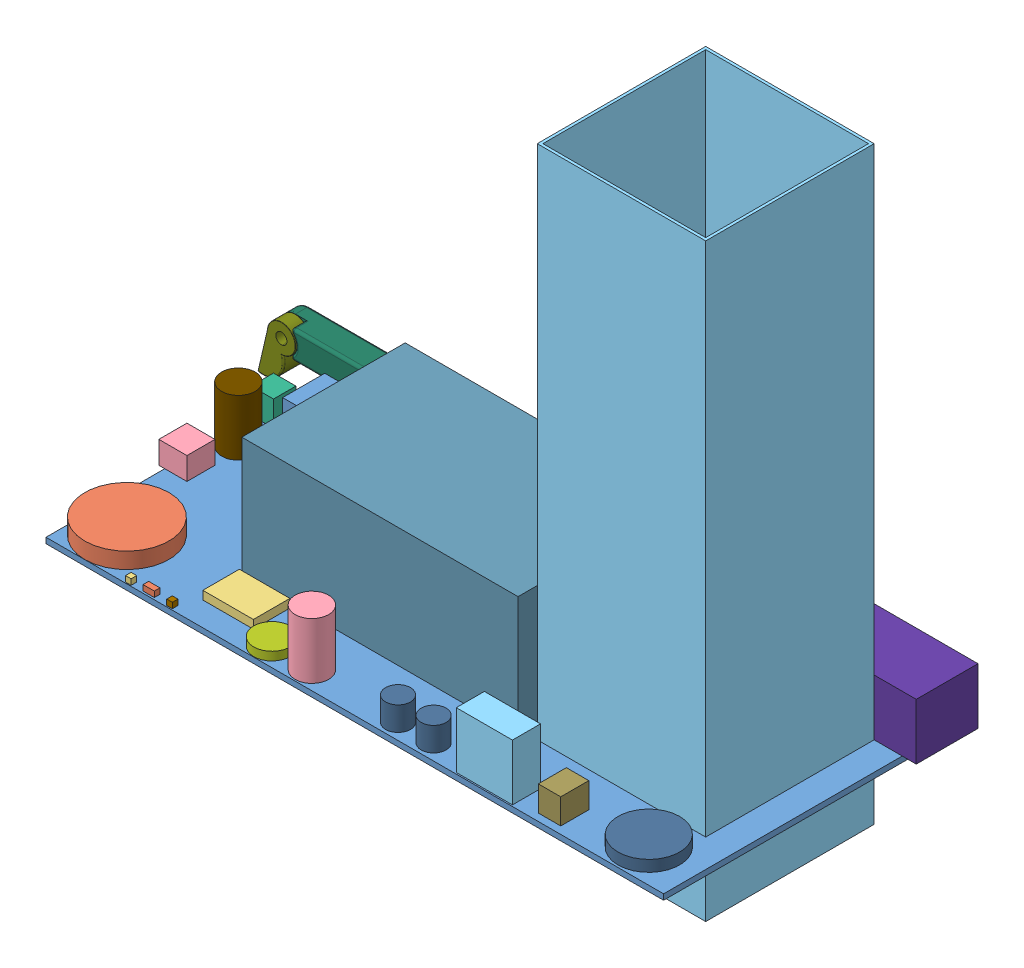
SolidWorks assembly layout_Assem1_rev2, configuration Default. Lengths in mm.
Overall size (2479.25 2100 1119.03).
31 component instances, 28 part files, 39 mates.
Components (placement in the parent):
- Rover_base-1: Rover_base [Default] at (-1064.6676 -0.8898 562.4151) size (2200 20 1100)
- Neutron_spectrometer-1: Neutron_spectrometer [Default] at (-926.7762 19.1102 412.2415) size (300 57 300)
- Neutron_spectrometer_electronics-1: Neutron_spectrometer_electronics [Default] at (-591.6675 19.1102 476.7062) size (180 30 130)
- gc-1: gc [Default] at (-1085.6976 19.1102 139.436) size (100 80 100)
- svr_box-1: svr_box [Default] at (435.3324 -241.6306 312.4151) size (600 2100 600)
- xrf-1: xrf [Default] at (-995.9409 19.1102 -179.1913) size (80 90 80)
- geotechnical_exp-1: geotechnical_exp [Default] at (-326.3032 19.1102 495.7882) x (0.972542 0 0.232729) z (-0.232729 0 0.972542) size (130 30 130)
- penetrometer_3-1: penetrometer_3 [Default] at (226.7911 19.1102 -521.6787) x (-0.361814 0 0.93225) z (-0.93225 0 -0.361814) size (20 40 20)
- penetrometer_3-2: penetrometer_3 [Default] at (171.3766 19.1102 -523.8951) size (20 40 20)
- penetrometer_3-3: penetrometer_3 [Default] at (128.071 19.1102 -518.5402) x (0.588244 0 -0.808683) z (0.808683 0 0.588244) size (20 40 20)
- power-1: power [Default] at (-481.4265 19.1102 -288.1678) size (180 90 96)
- geotechnical_exp_vane-1: geotechnical_exp_vane [Default] at (965.2252 19.1102 444.9326) size (220 40 220)
- Magnents-1: Magnents [Default] at (-1020.4169 -10.8898 98.2252) size (45 10 45)
- Becon-1: Becon [Default] at (742.9179 19.1102 536.3746) size (80 90 100)
- Belly Cam-1: Belly Cam [Default] at (-624.94 -100.8898 134.6139) size (150 100 150)
- lithium_battery_pack-1: lithium_battery_pack [Default] at (-598.6676 19.1102 330.9157) size (984 426 582)
- arm-1: arm [Default] at (-1208.8877 19.1102 -520.2644) x (-1 0 0) z (0 0 -1) size (1100 100 100)
- scoop-1: scoop [Default] at (-1258.8868 69.4182 -520.2644) x (0.225074 0.974342 0) z (0.974342 -0.225074 0) size (211.36 101.82 100)
- drill-1: drill [Default] at (1185.3324 19.1102 -287.5849) size (500 200 220)
- ap spectrometer-1: ap spectrometer [Default] at (-1001.9092 219.1102 -60.2814) x (0.2867 0 0.958021) z (0 -1 0) size (120 120 200)
- eprs-1: eprs [Default] at (-873.9785 19.1102 -239.8403) size (200 200 150)
- helium 3 sensor-1: helium 3 sensor [Default] at (-685.7595 19.1102 535.5303) size (40 20 20)
- ir bolometer-1: ir bolometer [Default] at (-784.8936 19.1102 538.9968) size (20 20 20)
- gamma ray spectrometer-1: gamma ray spectrometer [Default] at (-182.4638 19.1102 497.4632) x (0.580646 0 0.814156) z (0 1 0) size (120 120 200)
- langmuir probe-1: langmuir probe [Default] at (391.7791 19.1102 457.3324) size (200 200 100)
- particle counter-1: particle counter [Default] at (636.3286 19.1102 -531.248) x (0 0 1) z (-1 0 0) size (200 300 300)
- pes-1: pes [Default] at (-49.2556 19.1102 -529.0851) size (100 200 100)
- tuneable diode laser-1: tuneable diode laser [Default] at (299.0429 19.1102 -537.8756) size (10 10 10)
- uv imaging-1: uv imaging [Default] at (-638.9228 19.1102 538.0436) size (20 20 20)
- IMU_2-1: IMU_2 [Default] at (260.0364 19.1102 506.2504) size (88.9 85.09 88.9)
- IMU_2-2: IMU_2 [Default] at (133.304 19.1102 506.3815) size (88.9 85.09 88.9)
Mates (geometry in assembly coordinates):
- Coincident2: coincident anti-aligned: plane of Rover_base-1 through (-1064.6676 19.1102 -537.5849) normal (0 1 0); plane of Neutron_spectrometer-1 through (-926.7762 19.1102 412.2415) normal (0 -1 0)
- Coincident6: coincident anti-aligned: plane of Rover_base-1 through (-1064.6676 19.1102 -537.5849) normal (0 1 0); plane of Neutron_spectrometer_electronics-1 through (-591.6675 19.1102 346.7062) normal (0 -1 0)
- Coincident7: coincident anti-aligned: plane of Rover_base-1 through (-1064.6676 19.1102 -537.5849) normal (0 1 0); plane of power-1 through (-481.4265 19.1102 -384.1678) normal (0 -1 0)
- Coincident8: coincident anti-aligned: plane of Rover_base-1 through (-1064.6676 19.1102 -537.5849) normal (0 1 0); plane of gc-1 through (-1085.6976 19.1102 39.436) normal (0 -1 0)
- Coincident9: coincident aligned: plane of Rover_base-1 through (-1064.6676 19.1102 -537.5849) normal (0 1 0); circle of geotechnical_exp-1 centre (-326.3032 19.1102 495.7882) axis (0 1 0)
- Coincident10: coincident anti-aligned: plane of Rover_base-1 through (-1064.6676 19.1102 -537.5849) normal (0 1 0); plane of xrf-1 through (-995.9409 19.1102 -179.1913) normal (0 -1 0)
- Coincident11: coincident aligned: plane of Rover_base-1 through (-1064.6676 19.1102 -537.5849) normal (0 1 0); circle of penetrometer_3-3 centre (128.071 19.1102 -518.5402) axis (0 1 0)
- Coincident12: coincident anti-aligned: plane of Rover_base-1 through (-1064.6676 19.1102 -537.5849) normal (0 1 0); plane of penetrometer_3-2 through (171.3766 19.1102 -523.8951) normal (0 -1 0)
- Coincident13: coincident aligned: plane of Rover_base-1 through (-1064.6676 19.1102 -537.5849) normal (0 1 0); circle of penetrometer_3-1 centre (226.7911 19.1102 -521.6787) axis (0 1 0)
- Coincident14: coincident anti-aligned: plane of Rover_base-1 through (-1064.6676 19.1102 -537.5849) normal (0 1 0); plane of geotechnical_exp_vane-1 through (965.2252 19.1102 444.9326) normal (0 -1 0)
- Coincident15: coincident anti-aligned: plane of Rover_base-1 through (-1064.6676 -0.8898 -537.5849) normal (0 -1 0); plane of Magnents-1 through (-1020.4169 -0.8898 98.2252) normal (0 1 0)
- Coincident16: coincident anti-aligned: plane of Rover_base-1 through (-1064.6676 19.1102 -537.5849) normal (0 1 0); plane of Becon-1 through (742.9179 19.1102 536.3746) normal (0 -1 0)
- Coincident18: coincident: line of Rover_base-1; plane of svr_box-1 through (435.3324 1858.3694 312.4151) normal (-1 0 0)
- Coincident20: coincident: line of Rover_base-1; plane of svr_box-1 through (435.3324 1858.3694 -287.5849) normal (0 0 -1)
- Perpendicular2: perpendicular: line of Rover_base-1; line of svr_box-1
- Perpendicular3: perpendicular: line of Rover_base-1; line of svr_box-1
- Perpendicular4: perpendicular: line of Rover_base-1; line of svr_box-1
- Coincident21: coincident anti-aligned: plane of Rover_base-1 through (-1064.6676 19.1102 -537.5849) normal (0 1 0); plane of lithium_battery_pack-1 through (-598.6676 19.1102 -251.0843) normal (0 -1 0)
- Distance1: distance = 50 mm anti-aligned: plane of svr_box-1 through (435.3324 1858.3694 312.4151) normal (-1 0 0); plane of lithium_battery_pack-1 through (385.3324 445.1102 330.9157) normal (1 0 0)
- Coincident23: coincident anti-aligned: plane of Rover_base-1 through (-1064.6676 19.1102 -537.5849) normal (0 1 0); plane of arm-1 through (-1208.8877 19.1102 -420.2644) normal (0 -1 0)
- Distance2: distance = 100 mm: line of Rover_base-1; point of arm-1
- Distance3: distance = 20 mm: line of Rover_base-1; line of arm-1
- Coincident27: coincident aligned: circle of arm-1 centre (-1208.8877 69.1102 -470.2644) axis (0 0 1); circle of scoop-1 centre (-1208.8877 69.1102 -470.2644) axis (0 0 1)
- Coincident28: coincident anti-aligned: plane of Rover_base-1 through (-1064.6676 19.1102 -537.5849) normal (0 1 0); plane of drill-1 through (1185.3324 19.1102 -507.5849) normal (0 -1 0)
- Coincident29: coincident anti-aligned: plane of svr_box-1 through (435.3324 1858.3694 -287.5849) normal (0 0 -1); plane of drill-1 through (1185.3324 219.1102 -287.5849) normal (0 0 1)
- Distance4: distance = 50 mm: line of Rover_base-1; plane of drill-1 through (1185.3324 219.1102 -287.5849) normal (1 0 0)
- Coincident31: coincident anti-aligned: plane of Rover_base-1 through (-1064.6676 19.1102 -537.5849) normal (0 1 0); plane of ap spectrometer-1 through (-1001.9092 19.1102 -60.2814) normal (0 -1 0)
- Coincident32: coincident anti-aligned: plane of Rover_base-1 through (-1064.6676 19.1102 -537.5849) normal (0 1 0); plane of eprs-1 through (-873.9785 19.1102 -89.8403) normal (0 -1 0)
- Coincident33: coincident anti-aligned: plane of Rover_base-1 through (-1064.6676 19.1102 -537.5849) normal (0 1 0); plane of helium 3 sensor-1 through (-725.7595 19.1102 555.5303) normal (0 -1 0)
- Coincident34: coincident anti-aligned: plane of Rover_base-1 through (-1064.6676 19.1102 -537.5849) normal (0 1 0); plane of ir bolometer-1 through (-784.8936 19.1102 558.9968) normal (0 -1 0)
- Coincident36: coincident anti-aligned: plane of Rover_base-1 through (-1064.6676 19.1102 -537.5849) normal (0 1 0); plane of gamma ray spectrometer-1 through (-182.4638 19.1102 497.4632) normal (0 -1 0)
- Coincident37: coincident anti-aligned: plane of Rover_base-1 through (-1064.6676 19.1102 -537.5849) normal (0 1 0); plane of langmuir probe-1 through (391.7791 19.1102 557.3324) normal (0 -1 0)
- Coincident38: coincident: plane of Rover_base-1 through (-1064.6676 19.1102 -537.5849) normal (0 1 0); plane of particle counter-1 through (336.3286 19.1102 -531.248) normal (0 -1 0)
- Parallel1: parallel: line of Rover_base-1; plane of particle counter-1 through (336.3286 319.1102 -531.248) normal (0 0 -1)
- Coincident40: coincident anti-aligned: plane of Rover_base-1 through (-1064.6676 19.1102 -537.5849) normal (0 1 0); plane of pes-1 through (-49.2556 19.1102 -429.0851) normal (0 -1 0)
- Coincident41: coincident anti-aligned: plane of Rover_base-1 through (-1064.6676 19.1102 -537.5849) normal (0 1 0); plane of tuneable diode laser-1 through (289.0429 19.1102 -527.8756) normal (0 -1 0)
- Coincident42: coincident anti-aligned: plane of Rover_base-1 through (-1064.6676 19.1102 -537.5849) normal (0 1 0); plane of uv imaging-1 through (-638.9228 19.1102 558.0436) normal (0 -1 0)
- Coincident43: coincident anti-aligned: plane of Rover_base-1 through (-1064.6676 19.1102 -537.5849) normal (0 1 0); plane of IMU_2-2 through (133.304 19.1102 506.3815) normal (0 -1 0)
- Coincident44: coincident anti-aligned: plane of Rover_base-1 through (-1064.6676 19.1102 -537.5849) normal (0 1 0); plane of IMU_2-1 through (260.0364 19.1102 506.2504) normal (0 -1 0)
